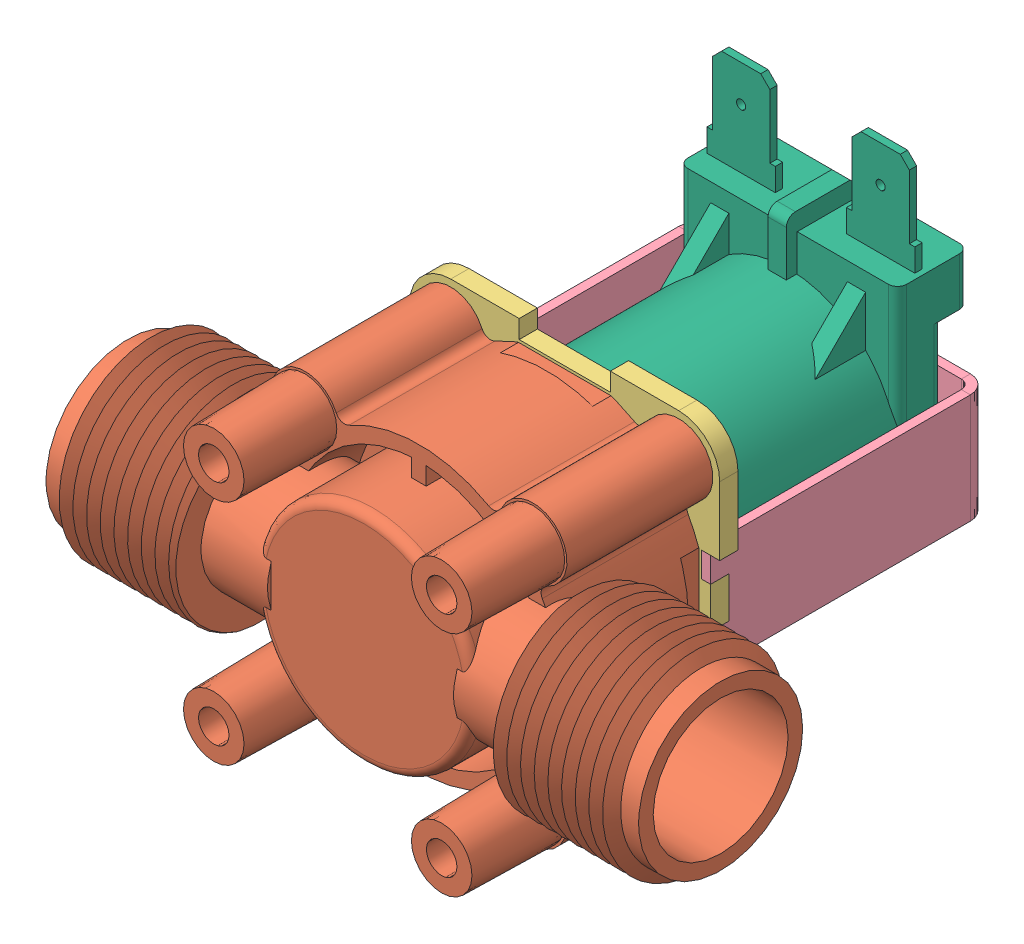
SolidWorks assembly SELENOID VALVE, configuration Default. Lengths in mm.
Overall size (65 43.5 58.61).
10 component instances, 9 part files, 0 mates.
Components (placement in the parent):
- SELENOID VALVE.stp-1: SELENOID VALVE.stp [Default] at origin size (65 43.5 58.61)
  - CORE.stp-1: CORE.stp [Default] at (19.4449 -2.9132 -6.95) x (0 0 1) z (1 0 0) size (23 6 6)
  - FILTER.stp-1: FILTER.stp [Default] at (40.4449 -2.9132 27.7) x (0 0 1) z (-1 0 0)
  - HOUSING.stp-1: HOUSING.stp [Default] at (19.4449 -2.9132 12.3) size (65 32.5 26.1)
  - PLATE 1.stp-1: PLATE 1.stp [Default] at (19.4449 -2.9132 10.3) x (0 -1 0) z (0 0 1) size (34 34 2)
  - PLATE 2.stp-1: PLATE 2.stp [Default] at (19.4449 -2.9132 -17.2) x (0 1 0) z (0 0 -1) size (23.67 32 30.5)
  - RAIL.stp-1: RAIL.stp [Default] at (19.4449 -2.9132 12.3) x (0 0 -1) z (0.972765 0.231794 0) size (36.3 26.4 26.4)
  - SELENOID.stp-1: SELENOID.stp [Default] at (19.4449 -2.9132 10.3) x (-1 0 0) z (0 0 -1) size (24.47 38.74 30.62)
  - VALCE.stp-1: VALCE.stp [Default] at (19.4449 -2.9132 13.8) x (0 0 1) z (1 0 0) size (9.3 22.7 22.7)
  - VALVE RUBBER.stp-1: VALVE RUBBER.stp [Default] at (19.4449 -2.9132 18.3) x (0 0 1) z (1 0 0) size (4 26.7 26.7)
